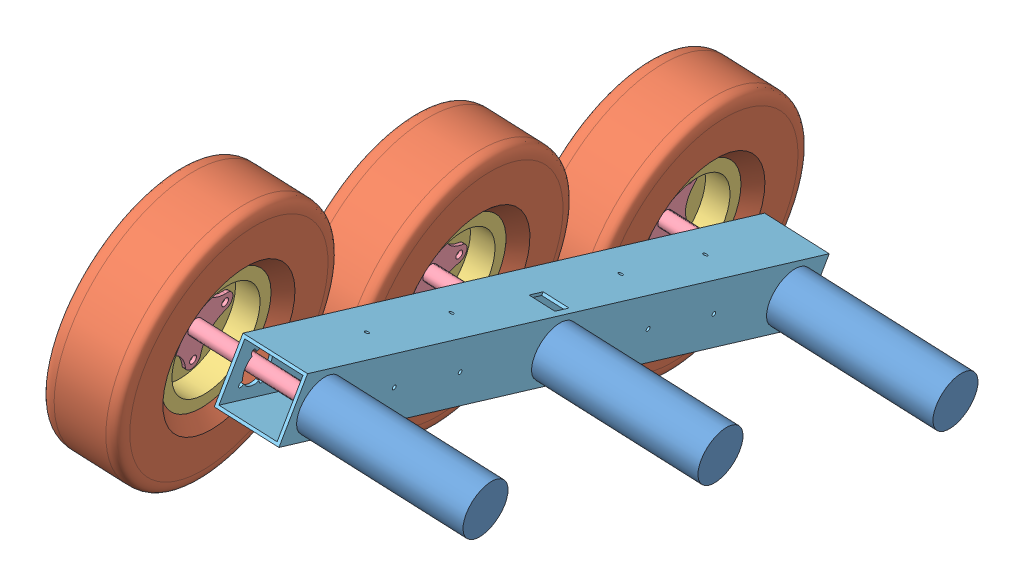
SolidWorks assembly Final ATR Drivetrain Assembly V4, configuration Default. Lengths in mm.
Overall size (438.43 562.1 906.16).
16 component instances, 5 part files, 24 mates.
Components (placement in the parent):
- Prototype IG52 Motor-2: Prototype IG52 Motor [Default] at (136.0831 289.3515 1314.1326) x (-0.161663 -0.911843 -0.37737) z (-0.986379 0.137535 0.09023) size (52 52 188.5)
- Prototype IG52 Motor-3: Prototype IG52 Motor [Default] at (49.8565 53.6078 730.8532) x (0.161663 0.911843 0.37737) z (-0.986379 0.137535 0.09023) size (52 52 188.5)
- Prototype IG52 Motor-4: Prototype IG52 Motor [Default] at (92.9698 171.4797 1022.4929) x (0.030374 -0.386816 0.921657) z (-0.986379 0.137535 0.09023) size (52 52 188.5)
- Prototype ATR Wheel Assembly V3-2: Prototype ATR Wheel Assembly V3 [Default] at (-399.1281 178.3509 892.6613) x (0.986379 -0.137535 -0.09023) z (0.10164 0.078317 0.991734) size (76.2 254.04 254.04)
  - Prototype ATR Tire V3-2: Prototype ATR Tire V3 [Default] at (184.4272 45.0149 178.2368) size (76.2 254.04 254.04)
  - Prototype ATR Wheel Rim V3-2: Prototype ATR Wheel Rim V3 [Default] at (184.4272 45.0149 178.2368) size (50.8 127 127)
- Prototype ATR Wheel Hub V3-2: Prototype ATR Wheel Hub V3 [Default] at (-188.7656 210.7633 1048.2648) x (0.10164 0.078317 0.991734) z (-0.986379 0.137535 0.09023) size (88.14 88.14 132.08)
- Prototype ATR Wheel Assembly V3-3: Prototype ATR Wheel Assembly V3 [Default] at (-311.9437 380.336 1537.868) x (0.986379 -0.137535 -0.09023) z (-0.076132 0.104531 -0.991603) size (76.2 254.04 254.04)
  - Prototype ATR Tire V3-2: Prototype ATR Tire V3 [Default] at (184.4272 45.0149 178.2368) size (76.2 254.04 254.04)
  - Prototype ATR Wheel Rim V3-2: Prototype ATR Wheel Rim V3 [Default] at (184.4272 45.0149 178.2368) size (50.8 127 127)
- Prototype ATR Wheel Hub V3-3: Prototype ATR Wheel Hub V3 [Default] at (-145.6523 328.6352 1339.9045) x (-0.076132 0.104531 -0.991603) z (-0.986379 0.137535 0.09023) size (88.14 88.14 132.08)
- Prototype ATR Wheel Assembly V3-4: Prototype ATR Wheel Assembly V3 [Default] at (-414.6895 36.8899 938.1726) x (0.986379 -0.137535 -0.09023) z (0.020928 0.649012 -0.760491) size (76.2 254.04 254.04)
  - Prototype ATR Tire V3-2: Prototype ATR Tire V3 [Default] at (184.4272 45.0149 178.2368) size (76.2 254.04 254.04)
  - Prototype ATR Wheel Rim V3-2: Prototype ATR Wheel Rim V3 [Default] at (184.4272 45.0149 178.2368) size (50.8 127 127)
- Prototype ATR Wheel Hub V3-4: Prototype ATR Wheel Hub V3 [Default] at (-231.8789 92.8915 756.6251) x (0.020928 0.649012 -0.760491) z (-0.986379 0.137535 0.09023) size (88.14 88.14 132.08)
- Final Aluminum Bar V4-1: Final Aluminum Bar V4 [Default] at (-51.7648 329.1712 1363.8303) x (-0.13579 -0.37125 -0.91855) z (-0.986379 0.137535 0.09023) size (704.85 63.5 63.5)
Mates (geometry in assembly coordinates):
- Coincident8: coincident anti-aligned: plane of Prototype ATR Wheel Assembly V3-2/Prototype ATR Wheel Rim V3-2 through (-192.0226 211.2175 1048.5627) normal (0.986379 -0.137535 -0.09023); plane of Prototype ATR Wheel Hub V3-2 through (-191.5252 227.545 1029.1121) normal (-0.986379 0.137535 0.09023)
- Coincident9: coincident anti-aligned: circle of Prototype ATR Wheel Assembly V3-2/Prototype ATR Wheel Rim V3-2; circle of Prototype ATR Wheel Hub V3-2
- Coincident10: coincident anti-aligned: plane of Prototype IG52 Motor-4 through (-71.2622 194.3793 1037.5161) normal (-0.986379 0.137535 0.09023); plane of Prototype ATR Wheel Hub V3-2 through (-71.2622 194.3793 1037.5161) normal (0.986379 -0.137535 -0.09023)
- Concentric9: concentric aligned: cylinder of Prototype IG52 Motor-4 through (-92.9626 197.4051 1039.5011) axis (0.986379 -0.137535 -0.09023) radius 6; cylinder of Prototype ATR Wheel Hub V3-2 through (-96.3163 197.8727 1039.8079) axis (0.986379 -0.137535 -0.09023) radius 6
- Coincident11: coincident anti-aligned: circle of Prototype ATR Wheel Assembly V3-2/Prototype ATR Wheel Rim V3-2; circle of Prototype ATR Wheel Hub V3-2
- Concentric10: concentric anti-aligned: circle of Prototype ATR Wheel Assembly V3-3/Prototype ATR Wheel Rim V3-2; circle of Prototype ATR Wheel Hub V3-3
- Concentric11: concentric anti-aligned: circle of Prototype ATR Wheel Assembly V3-3/Prototype ATR Wheel Rim V3-2; circle of Prototype ATR Wheel Hub V3-3
- Coincident15: coincident anti-aligned: plane of Prototype ATR Wheel Assembly V3-3/Prototype ATR Wheel Rim V3-2 through (-148.9093 329.0893 1340.2024) normal (0.986379 -0.137535 -0.09023); plane of Prototype ATR Wheel Hub V3-3 through (-150.1608 309.5214 1356.3483) normal (-0.986379 0.137535 0.09023)
- Coincident16: coincident anti-aligned: plane of Prototype IG52 Motor-2 through (-28.1489 312.2511 1329.1558) normal (-0.986379 0.137535 0.09023); plane of Prototype ATR Wheel Hub V3-3 through (-28.1489 312.2511 1329.1558) normal (0.986379 -0.137535 -0.09023)
- Concentric12: concentric aligned: cylinder of Prototype IG52 Motor-2 through (-49.8492 315.2769 1331.1408) axis (0.986379 -0.137535 -0.09023) radius 6; cylinder of Prototype ATR Wheel Hub V3-3 through (-53.2029 315.7445 1331.4476) axis (0.986379 -0.137535 -0.09023) radius 6
- Concentric13: concentric anti-aligned: circle of Prototype ATR Wheel Assembly V3-4/Prototype ATR Wheel Rim V3-2; circle of Prototype ATR Wheel Hub V3-4
- Concentric14: concentric anti-aligned: circle of Prototype ATR Wheel Assembly V3-4/Prototype ATR Wheel Rim V3-2; circle of Prototype ATR Wheel Hub V3-4
- Coincident19: coincident anti-aligned: plane of Prototype ATR Wheel Assembly V3-4/Prototype ATR Wheel Rim V3-2 through (-201.0804 88.5971 753.8078) normal (0.986379 -0.137535 -0.09023); plane of Prototype ATR Wheel Hub V3-4 through (-204.3867 63.5017 755.9171) normal (-0.986379 0.137535 0.09023)
- Coincident20: coincident anti-aligned: plane of Prototype IG52 Motor-3 through (-80.3201 71.7589 742.7611) normal (-0.986379 0.137535 0.09023); plane of Prototype ATR Wheel Hub V3-4 through (-80.3201 71.7589 742.7611) normal (0.986379 -0.137535 -0.09023)
- Concentric15: concentric aligned: cylinder of Prototype IG52 Motor-3 through (-102.0204 74.7847 744.7462) axis (0.986379 -0.137535 -0.09023) radius 6; cylinder of Prototype ATR Wheel Hub V3-4 through (-105.3741 75.2523 745.053) axis (0.986379 -0.137535 -0.09023) radius 6
- Concentric16: concentric anti-aligned: cylinder of Prototype IG52 Motor-3 through (-64.2639 88.2078 749.1355) axis (-0.986379 0.137535 0.09023) radius 2.5; cylinder of Final Aluminum Bar V4-1 through (-170.8192 103.0653 758.8828) axis (0.986379 -0.137535 -0.09023) radius 2.625
- Concentric17: concentric aligned: cylinder of Prototype IG52 Motor-3 through (-80.3201 71.7589 742.7611) axis (0.986379 -0.137535 -0.09023) radius 16; cylinder of Final Aluminum Bar V4-1 through (-174.0525 84.8285 751.3354) axis (0.986379 -0.137535 -0.09023) radius 16
- Concentric18: concentric anti-aligned: cylinder of Prototype IG52 Motor-4 through (-59.0468 200.3277 1017.91) axis (-0.986379 0.137535 0.09023) radius 2.5; cylinder of Final Aluminum Bar V4-1 through (-131.5466 210.4366 1024.5419) axis (0.986379 -0.137535 -0.09023) radius 2.625
- Concentric20: concentric aligned: cylinder of Prototype IG52 Motor-4 through (-71.2622 194.3793 1037.5161) axis (0.986379 -0.137535 -0.09023) radius 16; cylinder of Final Aluminum Bar V4-1 through (-130.9391 202.7003 1042.9751) axis (0.986379 -0.137535 -0.09023) radius 16
- Coincident22: coincident anti-aligned: plane of Prototype IG52 Motor-4 through (-68.3031 193.9667 1037.2454) normal (-0.986379 0.137535 0.09023); plane of Final Aluminum Bar V4-1 through (-113.2114 92.2847 701.3057) normal (0.986379 -0.137535 -0.09023)
- Concentric21: concentric aligned: cylinder of Prototype IG52 Motor-2 through (-28.1489 312.2511 1329.1558) axis (0.986379 -0.137535 -0.09023) radius 16; cylinder of Final Aluminum Bar V4-1 through (-87.8258 320.5722 1334.6148) axis (0.986379 -0.137535 -0.09023) radius 16
- Concentric22: concentric anti-aligned: cylinder of Prototype IG52 Motor-2 through (-12.0927 328.7 1335.5302) axis (-0.986379 0.137535 0.09023) radius 2.5; cylinder of Final Aluminum Bar V4-1 through (-84.5926 338.809 1342.1622) axis (0.986379 -0.137535 -0.09023) radius 2.625
- Coincident23: coincident anti-aligned: plane of Prototype IG52 Motor-2 through (-25.1898 311.8385 1328.8851) normal (-0.986379 0.137535 0.09023); plane of Final Aluminum Bar V4-1 through (-113.2114 92.2847 701.3057) normal (0.986379 -0.137535 -0.09023)
- Coincident24: coincident anti-aligned: plane of Prototype IG52 Motor-3 through (-111.4164 76.0948 745.6057) normal (-0.986379 0.137535 0.09023); plane of Final Aluminum Bar V4-1 through (-113.2114 92.2847 701.3057) normal (0.986379 -0.137535 -0.09023)
